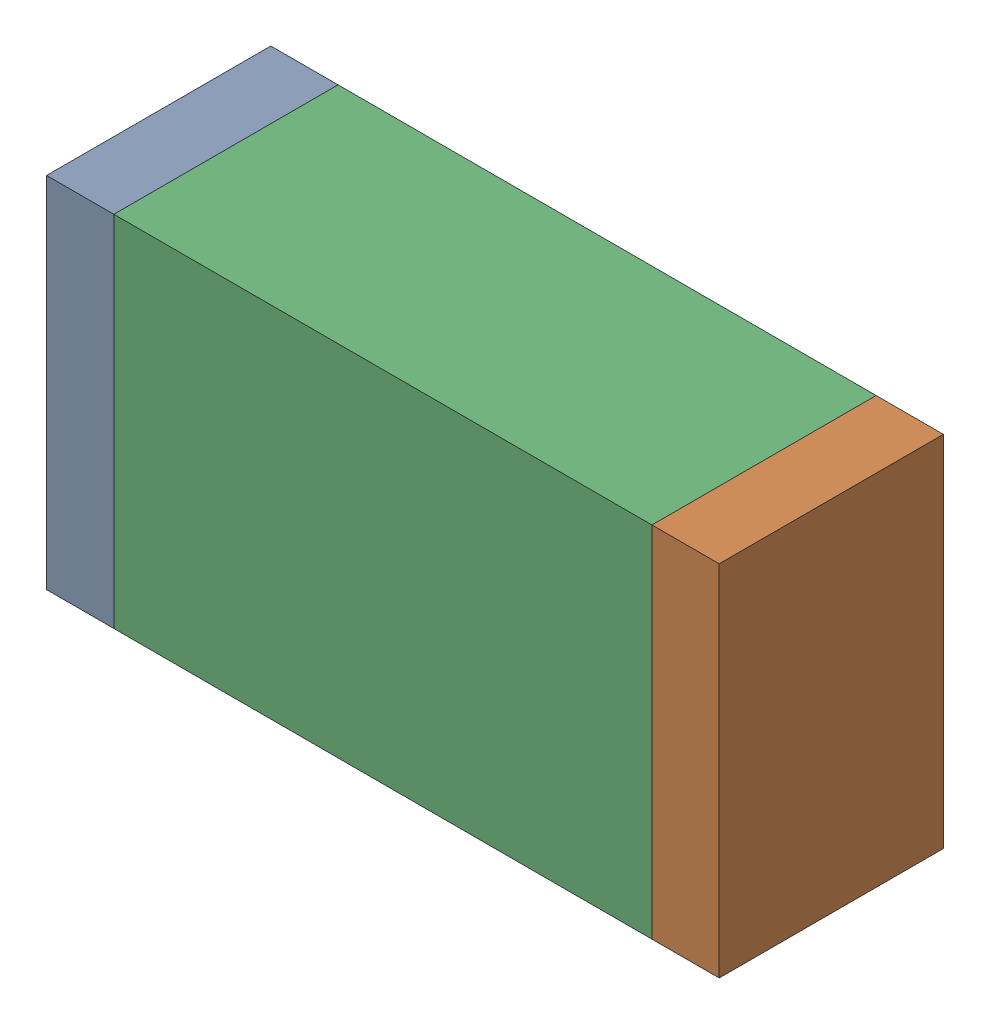
SolidWorks assembly R40, configuration Default. Lengths in mm.
Overall size (1.5 0.8 0.5).
6 component instances, 2 part files, 0 mates.
Components (placement in the parent):
- 836752496-1: 836752496 [Default] at (124.375 52.5 0) size (0.15 0.8 0.5)
  - Extruded_2-1: Extruded_2 [Default] at origin size (0.15 0.8 0.5)
- 836752496-2: 836752496 [Default] at (125.725 52.5 0) size (0.15 0.8 0.5)
  - Extruded_2-1: Extruded_2 [Default] at origin size (0.15 0.8 0.5)
- 836752368-1: 836752368 [Default] at (125.05 52.5 0) size (1.2 0.8 0.5)
  - Extruded-1: Extruded [Default] at origin size (1.2 0.8 0.5)
